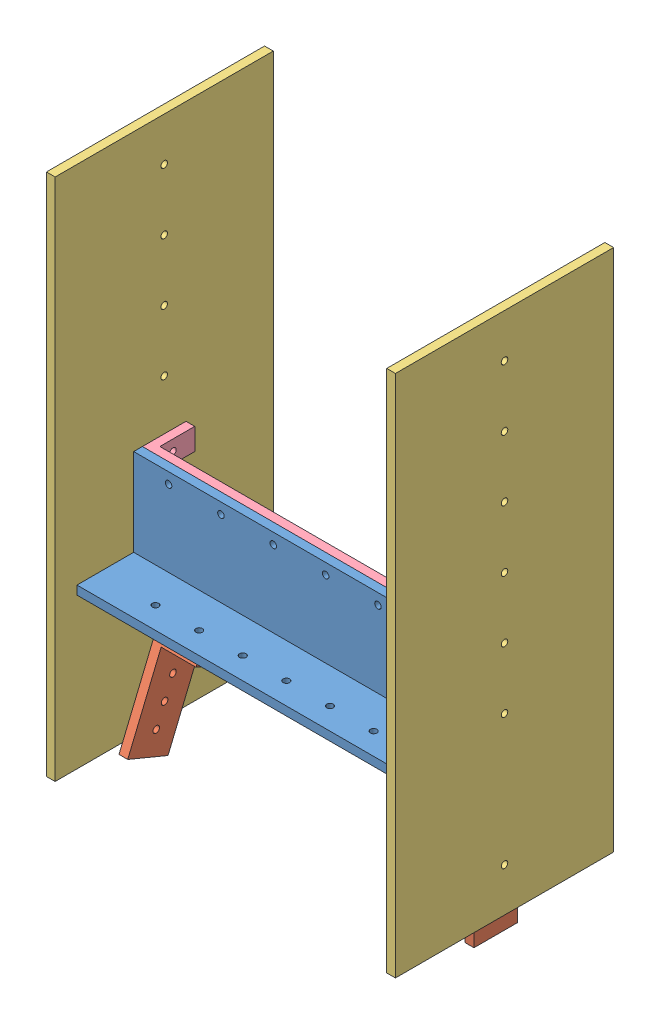
SolidWorks assembly assem0409, configuration Default. Lengths in mm.
Overall size (80 125.77 50).
7 component instances, 5 part files, 10 mates.
Components (placement in the parent):
- front-1: front [Default] at (-7.1438 42.5706 75.0992) size (76 22 15)
- leftRightInside-1: leftRightInside [Default] at (-7.1438 -4.8441 84.185) x (0 -0.383049 -0.923728) z (1 0 0) size (10 21 10)
- leftRightOutside-1: leftRightOutside [Default] at (70.8562 6.0706 45.0992) x (0 0 1) z (-1 0 0) size (50 120 2)
- mid-1: mid [Default] at (-5.1438 57.5706 73.0992) size (76 5 10)
- leftRightOutside-3: leftRightOutside [Default] at (-7.1438 6.0706 45.0992) x (0 0 1) z (-1 0 0) size (50 120 2)
- leftRightInside-2: leftRightInside [Default] at (68.8562 -8.6444 65.0992) x (0 0 1) z (-1 0 0) size (10 21 10)
- acoustic_guitar-2: acoustic_guitar [Default] at (1.4905 -130.3157 40.3289) size (1227.58 130.35 470.38) (hidden)
Mates (geometry in assembly coordinates):
- Coincident2: coincident anti-aligned: plane of leftRightOutside-1 through (68.8562 6.0706 45.0992) normal (-1 0 0); plane of mid-1 through (68.8562 57.5706 73.0992) normal (1 0 0)
- Concentric1: concentric anti-aligned: cylinder of leftRightOutside-1 through (68.8562 60.0706 70.0992) axis (1 0 0) radius 0.75; cylinder of mid-1 through (68.8562 60.0706 70.0992) axis (-1 0 0) radius 0.75
- Coincident6: coincident anti-aligned: plane of mid-1 through (-7.1438 57.5706 73.0992) normal (-1 0 0); plane of leftRightOutside-3 through (-7.1438 6.0706 45.0992) normal (1 0 0)
- Concentric2: concentric aligned: cylinder of mid-1 through (-7.1438 60.0706 70.0992) axis (1 0 0) radius 0.75; cylinder of leftRightOutside-3 through (-9.1438 60.0706 70.0992) axis (1 0 0) radius 0.75
- Coincident7: coincident anti-aligned: plane of leftRightInside-1; plane of leftRightOutside-3
- Concentric3: concentric anti-aligned: cylinder of leftRightInside-1 through (-5.1438 16.0706 70.0992) axis (-1 0 0) radius 0.75; cylinder of leftRightOutside-3 through (-9.1438 16.0706 70.0992) axis (1 0 0) radius 0.75
- Coincident8: coincident anti-aligned: plane of leftRightOutside-1 through (68.8562 6.0706 45.0992) normal (-1 0 0); plane of leftRightInside-2 through (68.8562 -8.6444 65.0992) normal (1 0 0)
- Concentric4: concentric aligned: cylinder of leftRightOutside-1 through (68.8562 16.0706 70.0992) axis (1 0 0) radius 0.75; cylinder of leftRightInside-2 through (66.8562 16.0706 70.0992) axis (1 0 0) radius 0.75
- Coincident10: coincident anti-aligned: plane of front-1 through (-7.1438 42.5706 75.0992) normal (0 0 -1); plane of mid-1 through (-5.1438 57.5706 75.0992) normal (0 0 1)
- Concentric6: concentric aligned: cylinder of front-1 through (60.8562 60.0706 77.0992) axis (0 0 -1) radius 0.75; cylinder of mid-1 through (60.8562 60.0706 75.0992) axis (0 0 -1) radius 0.75
